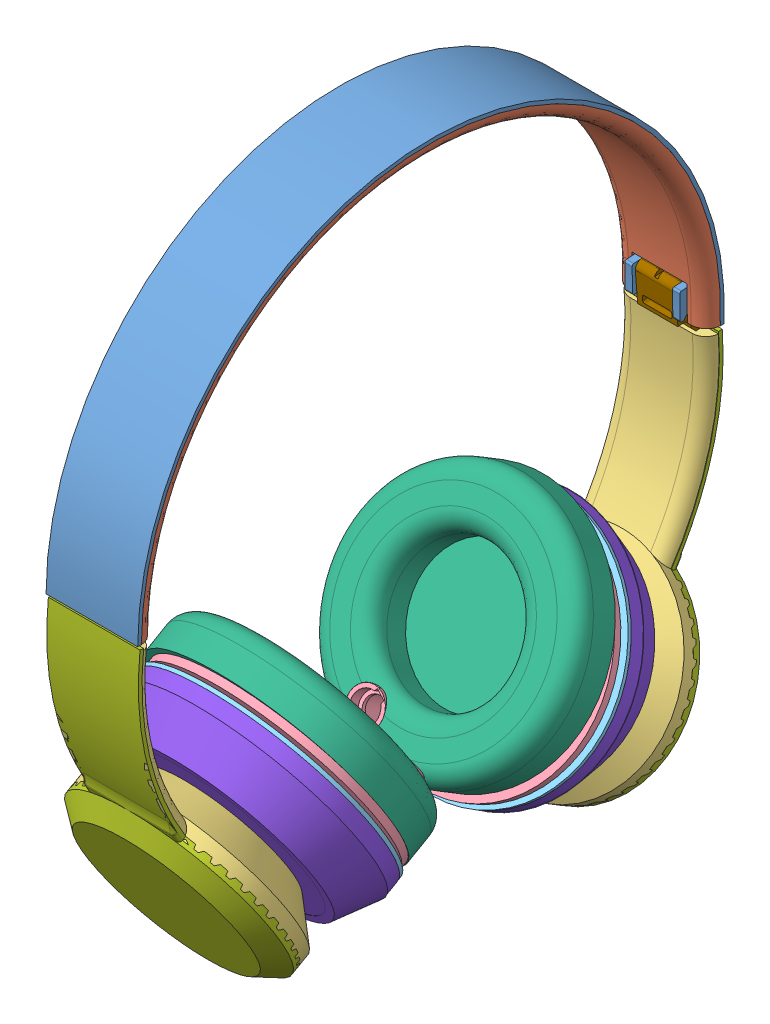
SolidWorks assembly Ensamblaje1, configuration Predeterminado. Lengths in mm.
Overall size (87.75 185.52 193.51).
17 component instances, 9 part files, 32 mates.
Components (placement in the parent):
- diadema-1: diadema [Predeterminado] at (31.7013 -36.0234 160) size (25 83.67 160)
- diadema parte abajo-1: diadema parte abajo [Predeterminado] at (25.9956 -39.1664 -0.4139) x (1 0 0) z (0 0.998946 -0.04589) size (25 158 82.63)
- parlante lado abajo-1: parlante lado abajo [Predeterminado] at (24.9727 -82.1342 131.7058) x (1 0 0) z (0 -0.868112 -0.496369) size (56 22.76 102.22)
- pieza-3-diadema-1: pieza-3-diadema [Predeterminado] at (22.0684 -94.4562 96.8464) x (-0.005123 -0.8681 -0.496363) z (-0.999987 0.004447 0.002543) size (63 21 63)
- Pieza2-diadema-2: Pieza2-diadema [Predeterminado] at (22.0684 -95.9453 99.4507) x (0.999987 -0.004447 -0.002543) z (-0.005123 -0.8681 -0.496363) size (65 3 65)
- pieza-4-diadema-1: pieza-4-diadema [Predeterminado] at (21.068 -94.5609 96.7865) x (0 -0.868112 -0.496369) z (1 0 0) size (65 12.35 65)
- parlante lado arriba-1: parlante lado arriba [Predeterminado] at (33.0254 -78.2173 124.8554) x (1 0 0) z (0 0.868112 0.496369) size (56 21.47 102.87)
- tapa-base-diadema-1: tapa-base-diadema [Predeterminado] at (22.0684 -97.6501 102.4323) x (0.999987 -0.004447 -0.002543) z (0 -0.496369 0.868112) size (65.23 65.23 16)
- pieza-joel-1: pieza-joel [Predeterminado] at (66.7553 -15.2078 143.9536) x (-1 0 0) z (0 -0.994449 0.105221) size (16.06 13.89 52.16)
- pieza-joel-2: pieza-joel [Predeterminado] at (-22.6186 -18.7012 -8.6425) x (1 0 0) z (0 -0.997019 -0.077152) size (16.06 13.89 52.16)
- pieza-4-diadema-4: pieza-4-diadema [Predeterminado] at (18.6682 -93.991 38.4593) x (0.918837 -0.336933 0.205464) z (-0.394638 -0.784481 0.478382) size (65 12.35 65)
- pieza-3-diadema-2: pieza-3-diadema [Predeterminado] at (20.7199 -95.8202 39.5747) x (0.866854 -0.42566 0.25957) z (0.498561 0.7401 -0.451318) size (63 21 63)
- Pieza2-diadema-3: Pieza2-diadema [Predeterminado] at (20.7199 -97.3821 37.0134) x (1 0 0) z (0 0.853777 -0.520639) size (65 3 65)
- parlante lado abajo-2: parlante lado abajo [Predeterminado] at (19.164 -85.2558 5.4868) x (-1 0 0) z (0 -0.853777 0.520639) size (56 22.76 102.22)
- Ensamblaje1^Ensamblaje1-1: Ensamblaje1^Ensamblaje1 [Predeterminado] at (11.1113 -81.1474 12.224) x (-1 0 0) z (0 0.853777 -0.520639) size (56 21.47 102.87) (virtual)
  - parlante lado arriba-1: parlante lado arriba [Predeterminado] at origin size (56 21.47 102.87)
- tapa-base-diadema-2: tapa-base-diadema [Predeterminado] at (20.7199 -99.1703 34.0811) x (0.999999 0.001418 -0.000865) z (0 -0.520639 -0.853777) size (65.23 65.23 16)
Mates (geometry in assembly coordinates):
- Concéntrica2: concentric anti-aligned: cylinder of diadema-1 through (22.0684 -36.0234 68.0025) axis (1 0 0) radius 79; cylinder of diadema parte abajo-1 through (13.5684 -36.0234 68.0025) axis (-1 0 0) radius 79
- Coincidente2: coincident anti-aligned: plane of diadema-1 through (14.5684 -40.2453 -23.898) normal (-1 0 0); plane of diadema parte abajo-1 through (14.5684 -36.0234 136.4911) normal (1 0 0)
- Coincidente3: coincident aligned: plane of diadema-1 through (31.7013 -36.0234 160) normal (0 -1 0); plane of diadema parte abajo-1 through (25.9956 -36.0234 136.4911) normal (0 -1 0)
- Concéntrica3: concentric anti-aligned: cylinder of Pieza2-diadema-2 through (22.0684 -96.4417 100.3188) axis (0 -0.496369 0.868112) radius 30.5; cylinder of tapa-base-diadema-1 through (22.0684 -77.3765 66.9752) axis (0 0.496369 -0.868112) radius 30.5
- Concéntrica4: concentric anti-aligned: cylinder of Pieza2-diadema-2 through (34.2095 -115.4116 90.6241) axis (0 0.496369 -0.868112) radius 2.5; cylinder of tapa-base-diadema-1 through (34.2095 -114.4188 88.8879) axis (0 -0.496369 0.868112) radius 2.5
- Concéntrica5: concentric anti-aligned: cylinder of Pieza2-diadema-2 through (34.4269 -78.5735 111.6874) axis (0 0.496369 -0.868112) radius 2.5; cylinder of tapa-base-diadema-1 through (34.4269 -77.5808 109.9512) axis (0 -0.496369 0.868112) radius 2.5
- Coincidente4: coincident anti-aligned: plane of Pieza2-diadema-2 through (22.0684 -96.4417 100.3188) normal (0 -0.496369 0.868112); plane of tapa-base-diadema-1 through (22.0684 -96.4417 100.3188) normal (0 0.496369 -0.868112)
- Coincidente5: coincident anti-aligned: plane of pieza-3-diadema-1 through (22.0684 -95.4489 98.5826) normal (0 -0.496369 0.868112); plane of Pieza2-diadema-2 through (22.0684 -95.4489 98.5826) normal (0 0.496369 -0.868112)
- Concéntrica6: concentric aligned: circle of pieza-3-diadema-1; circle of tapa-base-diadema-1
- Concéntrica7: concentric aligned: circle of pieza-3-diadema-1; circle of tapa-base-diadema-1
- Concéntrica8: concentric aligned: cylinder of pieza-3-diadema-1 through (45.608 -88.6045 86.3692) axis (0 -0.496369 0.868112) radius 4.96; cylinder of pieza-4-diadema-1 through (45.608 -88.6045 86.3692) axis (0 -0.496369 0.868112) radius 4.96
- Coincidente7: coincident anti-aligned: plane of pieza-3-diadema-1 through (22.0684 -94.4562 96.8464) normal (0 0.496369 -0.868112); plane of pieza-4-diadema-1 through (21.068 -94.5609 96.7865) normal (0 -0.496369 0.868112)
- Concéntrica11: concentric anti-aligned: cylinder of parlante lado arriba-1 through (22.0684 -45.5502 67.7231) axis (1 0 0) radius 79.1; cylinder of pieza-joel-1 through (22.0684 -45.5502 67.7231) axis (-1 0 0) radius 79
- Coincidente10: coincident aligned: plane of parlante lado arriba-1 through (33.0254 -38.6139 133.1688) normal (0 0.99443 -0.105395); plane of pieza-joel-1 through (66.7553 -37.224 146.2831) normal (0 0.99443 -0.105395)
- Coincidente13: coincident aligned: circle of diadema-1; circle of pieza-joel-1
- Coincidente15: coincident aligned: plane of diadema-1 through (34.5684 -40.2453 -23.898) normal (1 0 0); plane of parlante lado arriba-1 through (34.5684 -38.6139 133.1688) normal (1 0 0)
- Coincidente16: coincident anti-aligned: circle of parlante lado abajo-1; circle of parlante lado arriba-1
- Concéntrica17: concentric anti-aligned: circle of parlante lado abajo-1; circle of tapa-base-diadema-1
- Concéntrica19: concentric anti-aligned: cylinder of parlante lado abajo-1 through (22.0684 -102.1709 110.3388) axis (0 -0.496369 0.868112) radius 3.5; cylinder of tapa-base-diadema-1 through (22.0684 -109.8436 123.7578) axis (0 0.496369 -0.868112) radius 5
- Concéntrica23: concentric anti-aligned: cylinder of pieza-joel-2 through (22.0684 -46.883 68.4129) axis (1 0 0) radius 79; cylinder of Ensamblaje1^Ensamblaje1-1/parlante lado arriba-1 through (22.0684 -46.883 68.4129) axis (-1 0 0) radius 79.1
- Coincidente32: coincident aligned: plane of pieza-joel-2 through (-22.6186 -40.7743 -10.3505) normal (0 0.997006 0.077326); plane of Ensamblaje1^Ensamblaje1-1/parlante lado arriba-1 through (11.1113 -41.7941 2.7978) normal (0 0.997006 0.077326)
- Concéntrica27: concentric anti-aligned: cylinder of pieza-joel-2 through (22.0684 -46.883 68.4129) axis (1 0 0) radius 79; cylinder of Ensamblaje1^Ensamblaje1-1/parlante lado arriba-1 through (22.0684 -46.883 68.4129) axis (-1 0 0) radius 79.1
- Coincidente33: coincident aligned: plane of diadema-1 through (9.5684 -40.2453 -23.898) normal (-1 0 0); plane of Ensamblaje1^Ensamblaje1-1/parlante lado arriba-1 through (9.5684 -41.7941 2.7978) normal (-1 0 0)
- Coincidente34: coincident anti-aligned: circle of parlante lado abajo-2; circle of Ensamblaje1^Ensamblaje1-1/parlante lado arriba-1
- Coincidente35: coincident anti-aligned: plane of parlante lado abajo-2 through (19.164 -106.2443 24.8486) normal (0 0.520639 0.853777); plane of tapa-base-diadema-2 through (20.7199 -105.1917 24.2068) normal (0 -0.520639 -0.853777)
- Coincidente36: coincident anti-aligned: circle of Pieza2-diadema-3; circle of tapa-base-diadema-2
- Concéntrica30: concentric aligned: circle of pieza-3-diadema-2; circle of tapa-base-diadema-2
- Concéntrica31: concentric aligned: circle of pieza-3-diadema-2; circle of tapa-base-diadema-2
- Coincidente38: coincident anti-aligned: plane of pieza-3-diadema-2 through (20.7199 -96.8615 37.8672) normal (0 -0.520639 -0.853777); plane of Pieza2-diadema-3 through (20.7199 -96.8615 37.8672) normal (0 0.520639 0.853777)
- Concéntrica32: concentric aligned: cylinder of pieza-4-diadema-4 through (8.9838 -106.9945 60.4441) axis (0 -0.520639 -0.853777) radius 4.96; cylinder of pieza-3-diadema-2 through (8.9838 -106.9945 60.4441) axis (0 -0.520639 -0.853777) radius 4.96
- Coincidente39: coincident anti-aligned: plane of pieza-4-diadema-4 through (18.6682 -93.991 38.4593) normal (0 -0.520639 -0.853777); plane of pieza-3-diadema-2 through (20.7199 -95.8202 39.5747) normal (0 0.520639 0.853777)
- Coincidente41: coincident aligned: circle of diadema-1; circle of pieza-joel-2
